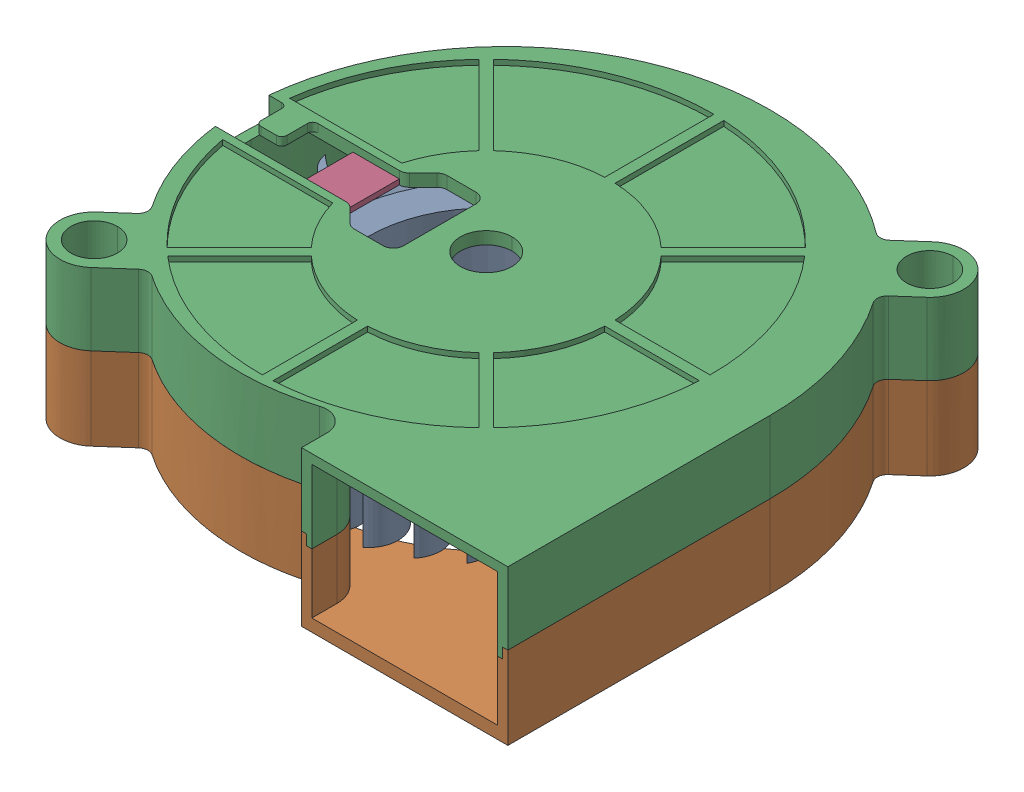
SolidWorks assembly Radial-Cooling-Fan-5015-DC12V, configuration 默认. Lengths in mm.
Overall size (51.62 15 51.07).
3 component instances, 3 part files, 0 mates.
Components (placement in the parent):
- turbine-1: turbine [默认] at (-35.3134 11.9845 -3.4094) x (-0.990476 0 -0.137682) z (-0.137682 0 0.990476) size (38.96 10.5 38.91)
- top-1: top [默认] at (-35.3134 0.1845 -3.4094) x (-1 0 0) z (0 0 1) size (51.31 8 51.07)
- bottom-1: bottom [默认] at (-35.3134 15.1845 -3.4094) x (-1 0 0) z (0 0 1) size (51.62 8.5 51.07)
